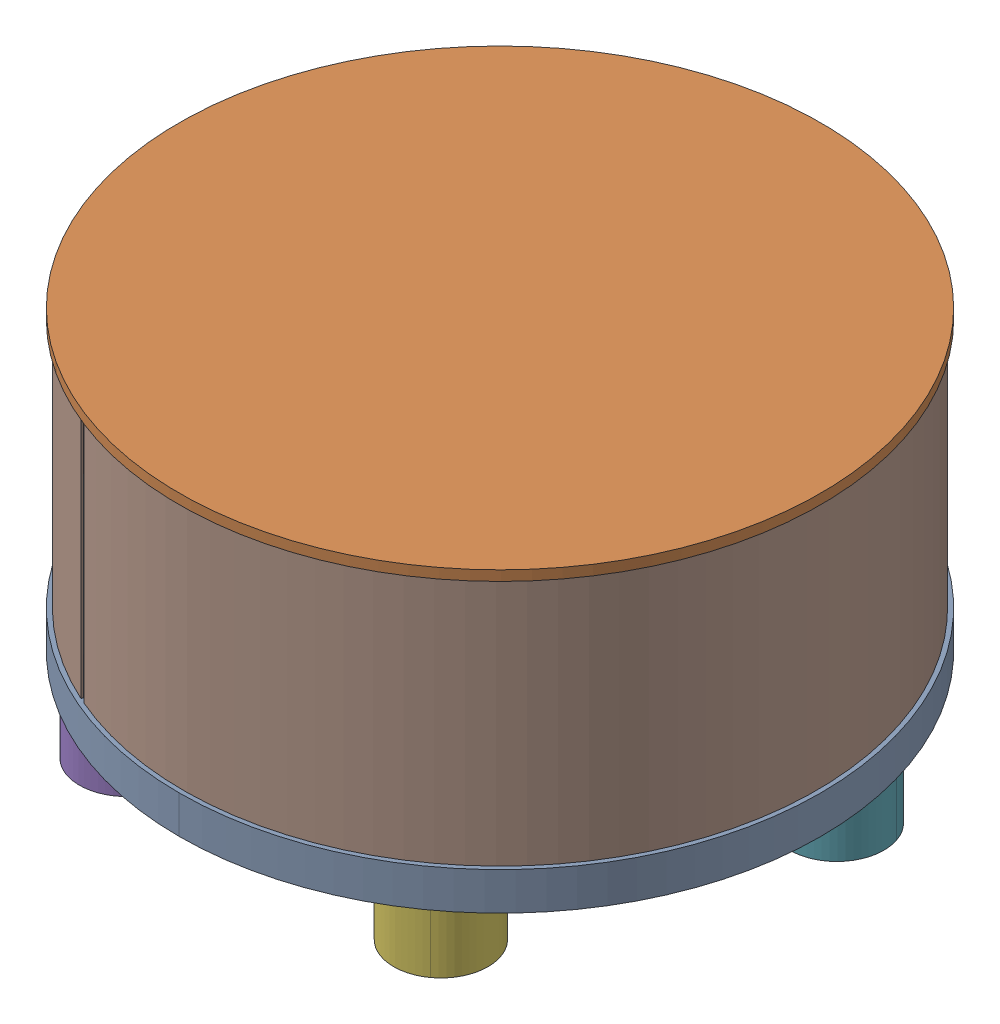
SolidWorks assembly IT-028-01 (DRIVE ASSEMBLY), configuration Default. Lengths in mm.
Overall size (705.9 286.38 705.9).
8 component instances, 4 part files, 0 mates.
Components (placement in the parent):
- IT-028-01-001 (500 DRIVE BASE)-1: IT-028-01-001 (500 DRIVE BASE) [Default] at origin size (510 60 510)
- IT-028-01-003 (500 DRIVE TOP)-1: IT-028-01-003 (500 DRIVE TOP) [Default] at (0 236.3816 0) x (-0.837169 0 -0.546944) z (-0.546944 0 0.837169) size (510 20 510)
- M12 AV PADS-1: M12 AV PADS [Default] at (0 -50 -212.5) size (75 70 75)
- M12 AV PADS-2: M12 AV PADS [Default] at (-202.0995 -50 -65.6661) x (0.309017 0 -0.951057) z (0.951057 0 0.309017) size (75 70 75)
- M12 AV PADS-3: M12 AV PADS [Default] at (-124.9044 -50 171.9161) x (-0.809017 0 -0.587785) z (0.587785 0 -0.809017) size (75 70 75)
- M12 AV PADS-4: M12 AV PADS [Default] at (124.9044 -50 171.9161) x (-0.809017 0 0.587785) z (-0.587785 0 -0.809017) size (75 70 75)
- M12 AV PADS-5: M12 AV PADS [Default] at (202.0995 -50 -65.6661) x (0.309017 0 0.951057) z (-0.951057 0 0.309017) size (75 70 75)
- IT-028-01-006 (COVER)-1: IT-028-01-006 (COVER) [Default] at (0 30 0) x (0.914466 0 0.404664) z (-0.404664 0 0.914466) size (503.2 198 503.19)
